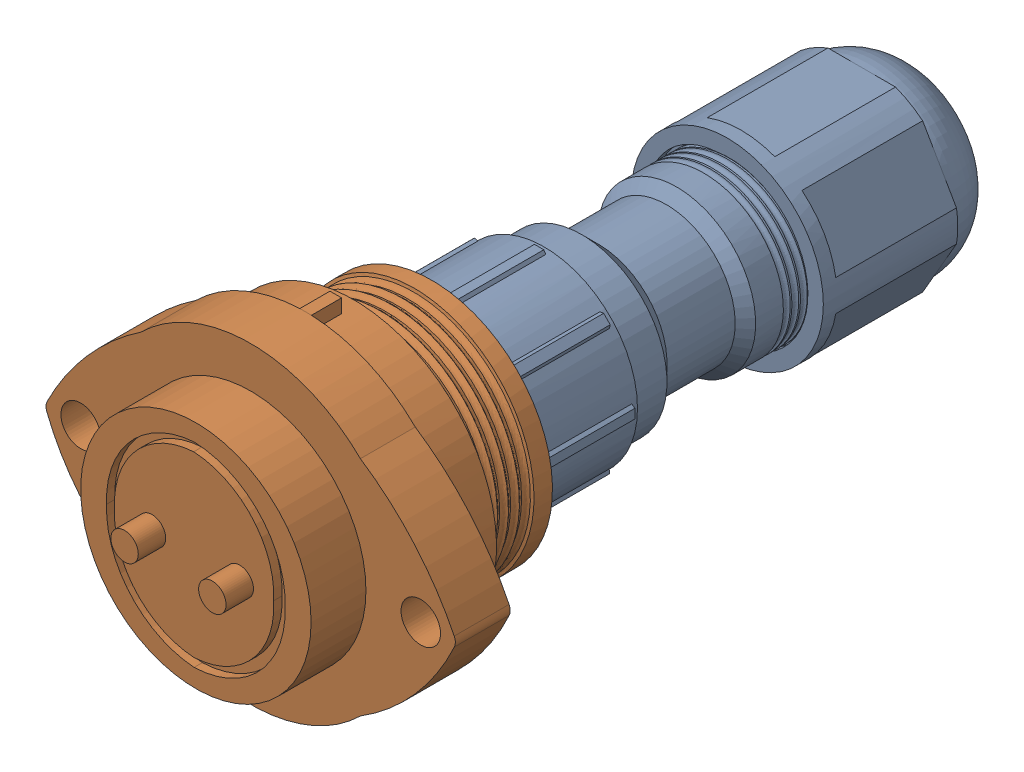
SolidWorks assembly 2 Pin Assembly, configuration Default. Lengths in mm.
Overall size (37.31 28.5 67.41).
2 component instances, 2 part files, 2 mates.
Components (placement in the parent):
- 2 pin connector female part-1: 2 pin connector female part [Default] at (-99.5483 24.8836 54.7023) size (17.52 17.52 48.16)
- 2 pin connector-1: 2 pin connector [Default] at (-99.5483 24.8836 71.4523) size (37.31 28.5 24)
Mates (geometry in assembly coordinates):
- Coincident2: coincident: plane of 2 pin connector female part-1 through (-96.2983 24.8836 57.9523) normal (0 0 1); plane of 2 pin connector-1 through (-96.4065 61.188 57.9523) normal (0 0 -1)
- Concentric5: concentric aligned: cylinder of 2 pin connector female part-1 through (-99.5483 24.8836 55.4523) axis (0 0 1) radius 5.65; cylinder of 2 pin connector-1 through (-99.5483 24.8836 54.9523) axis (0 0 1) radius 5.6
